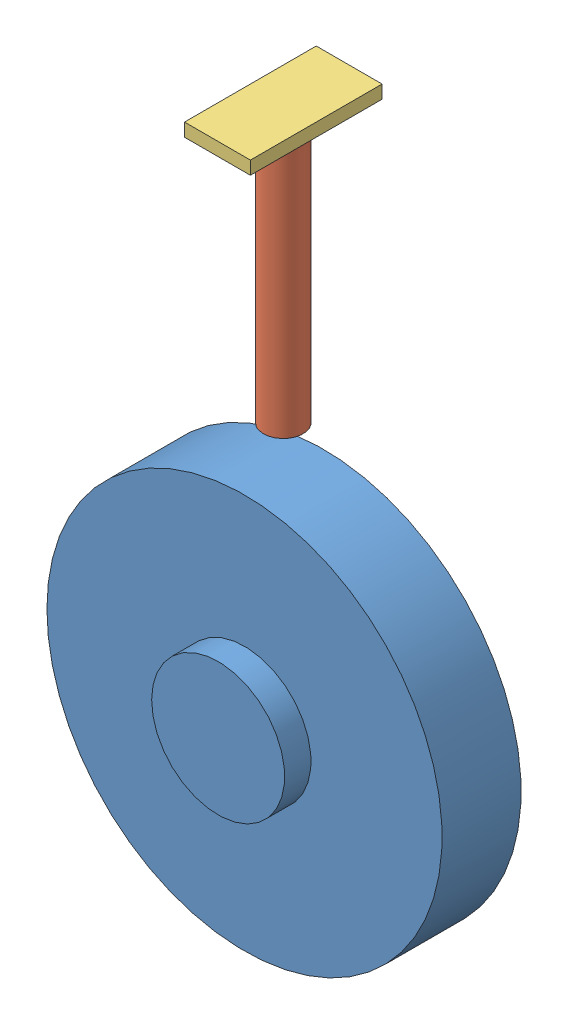
SolidWorks assembly Assem1, configuration Default. Lengths in mm.
Overall size (300 542.34 100).
3 component instances, 3 part files, 7 mates.
Components (placement in the parent):
- wheel-1: wheel [Default] at (79.1111 155.6289 198.2513) size (300 300 100)
- cylinder1-1: cylinder1 [Default] at (78.5861 337.9713 228.2513) x (0.914367 0 0.404887) z (-0.404887 0 0.914367) size (30 200 30)
- connector1-1: connector1 [Default] at (102.4634 537.9713 271.3651) x (0 0 -1) z (1 0 0) size (100 10 50)
Mates (geometry in assembly coordinates):
- Perpendicular1: perpendicular: plane of wheel-1 through (79.1111 155.6289 258.2513) normal (0 0 1); plane of cylinder1-1 through (78.5861 337.9713 228.2513) normal (0 -1 0)
- Perpendicular2: perpendicular: line of wheel-1 through (79.1111 155.6289 258.2513) axis (0 0 -1); line of cylinder1-1 through (78.5861 537.9713 228.2513) axis (0 -1 0)
- Coincident2: coincident anti-aligned: plane of cylinder1-1 through (78.5861 537.9713 228.2513) normal (0 1 0); plane of connector1-1 through (102.4634 537.9713 271.3651) normal (0 -1 0)
- Parallel1: parallel aligned: plane of wheel-1 through (79.1111 155.6289 258.2513) normal (0 0 1); plane of connector1-1 through (53.5861 547.9713 278.2513) normal (0 0 1)
- Width1: width: cylinder of connector1-1; plane of cylinder1-1 through (53.5861 547.9713 178.2513) normal (0 0 -1); cylinder of connector1-1 through (78.5861 537.9713 228.2513) axis (0 -1 0) radius 15
- Width2: width: plane of connector1-1 through (53.5861 547.9713 278.2513) normal (-1 0 0); plane of cylinder1-1 through (103.5861 547.9713 278.2513) normal (1 0 0); cylinder of connector1-1 through (78.5861 537.9713 228.2513) axis (0 -1 0) radius 15
- Width3: width: plane of wheel-1 through (79.1111 155.6289 258.2513) normal (0 0 1); plane of cylinder1-1 through (79.1111 155.6289 198.2513) normal (0 0 -1); cylinder of wheel-1 through (78.5861 537.9713 228.2513) axis (0 -1 0) radius 15
